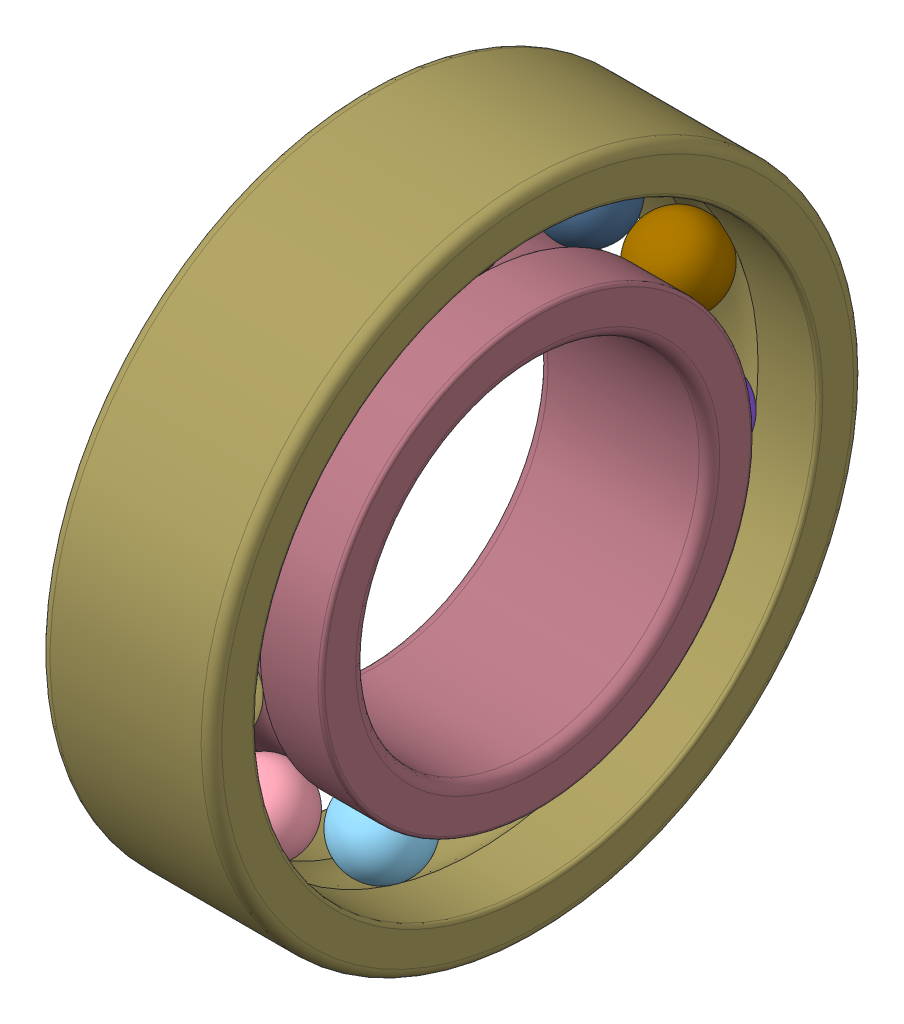
SolidWorks assembly RoulementAxeMoteur, configuration Défaut. Lengths in mm.
Overall size (5.01 19 19).
14 component instances, 14 part files, 0 mates.
Components (placement in the parent):
- 1_PART_61800_PART1_in_ASM_61800-1: 1_PART_61800_PART1_in_ASM_61800 [Défaut] at (2.5 6.0991 3.9196) size (3.2 3.01 3.02)
- 2_PART_61800_PART2_in_ASM_61800-1: 2_PART_61800_PART2_in_ASM_61800 [Défaut] at (2.5 3.0118 6.5948) size (3.23 3.28 3.31)
- 3_PART_61800_PART3_in_ASM_61800-1: 3_PART_61800_PART3_in_ASM_61800 [Défaut] at (2.5 -1.0318 7.1762) size (3.31 3.03 3.32)
- 4_PART_61800_PART3_in_ASM_61800-1: 4_PART_61800_PART3_in_ASM_61800 [Défaut] at (2.5 -4.7477 5.4792) size (3.18 3.13 3.12)
- 5_PART_61800_PART3_in_ASM_61800-1: 5_PART_61800_PART3_in_ASM_61800 [Défaut] at (2.5 -6.9563 2.0426) size (3.11 3.23 3.11)
- 6_PART_61800_PART3_in_ASM_61800-1: 6_PART_61800_PART3_in_ASM_61800 [Défaut] at (2.5 -6.9563 -2.0426) size (3.2 3.24 3.25)
- 7_PART_61800_PART3_in_ASM_61800-1: 7_PART_61800_PART3_in_ASM_61800 [Défaut] at (2.5 -4.7477 -5.4792) size (3.13 3.32 3.2)
- 8_PART_61800_PART3_in_ASM_61800-1: 8_PART_61800_PART3_in_ASM_61800 [Défaut] at (2.5 -1.0318 -7.1762) size (3.23 3.19 3.29)
- 9_PART_61800_PART3_in_ASM_61800-1: 9_PART_61800_PART3_in_ASM_61800 [Défaut] at (2.5 3.0118 -6.5948) size (3.19 2.92 2.97)
- 10_PART_61800_PART3_in_ASM_61800-1: 10_PART_61800_PART3_in_ASM_61800 [Défaut] at (2.5 6.0991 -3.9196) size (3.35 3.36 3.04)
- 11_PART_61800_PART3_in_ASM_61800-1: 11_PART_61800_PART3_in_ASM_61800 [Défaut] at (2.5 7.25 0) size (3.28 3.11 3.26)
- 12_PART_61800_PART3_in_ASM_61800-1: 12_PART_61800_PART3_in_ASM_61800 [Défaut] at (2.5 0 0) size (5 19 19)
- 13_PART_61800_PART3_in_ASM_61800-1: 13_PART_61800_PART3_in_ASM_61800 [Défaut] at (2.5 0 0) size (5.01 12.6 12.6)
- RoulementAxeMoteur-1: RoulementAxeMoteur [Défaut] at origin
